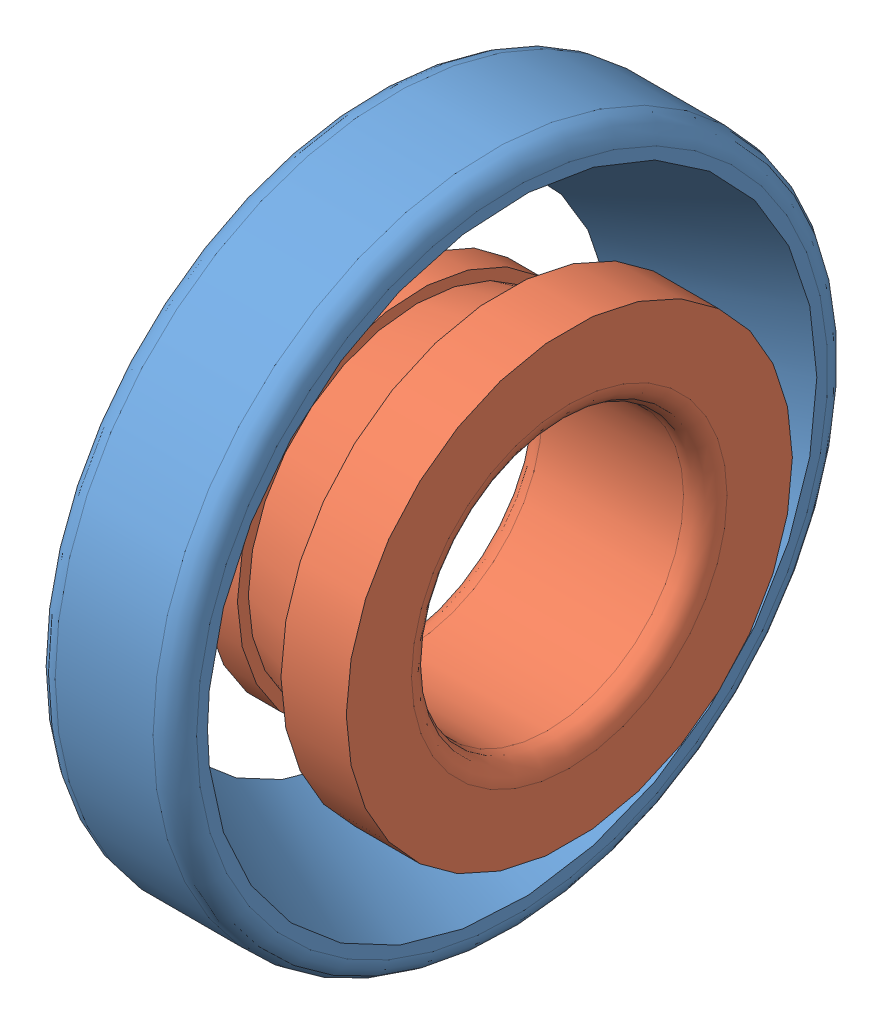
SolidWorks assembly Сборка1, configuration По умолчанию. Lengths in mm.
Overall size (18.25 62 62).
2 component instances, 2 part files, 4 mates.
Components (placement in the parent):
- Внешняя обойма^Сборка1-1: Внешняя обойма^Сборка1 [По умолчанию] at origin size (13 62 62) (virtual)
- Деталь11^Сборка1-1: Деталь11^Сборка1 [По умолчанию] at origin size (17 41 41) (virtual)
Mates (geometry in assembly coordinates):
- На месте1: in place: plane of ? through (0 0 0) normal (0 0 1); moOrthogonalPlaneRef_w of ? through (0 0 0) normal (0 1 0); plane of ? through (0 0 0) normal (1 0 0); unknown of ?
- Совпадение1: coincident: plane of ?; plane of assembly
- Совпадение2: coincident: plane of ? through (0 0 0) normal (0 1 0)
- Совпадение3: coincident: plane of ? through (0 0 0) normal (1 0 0)
